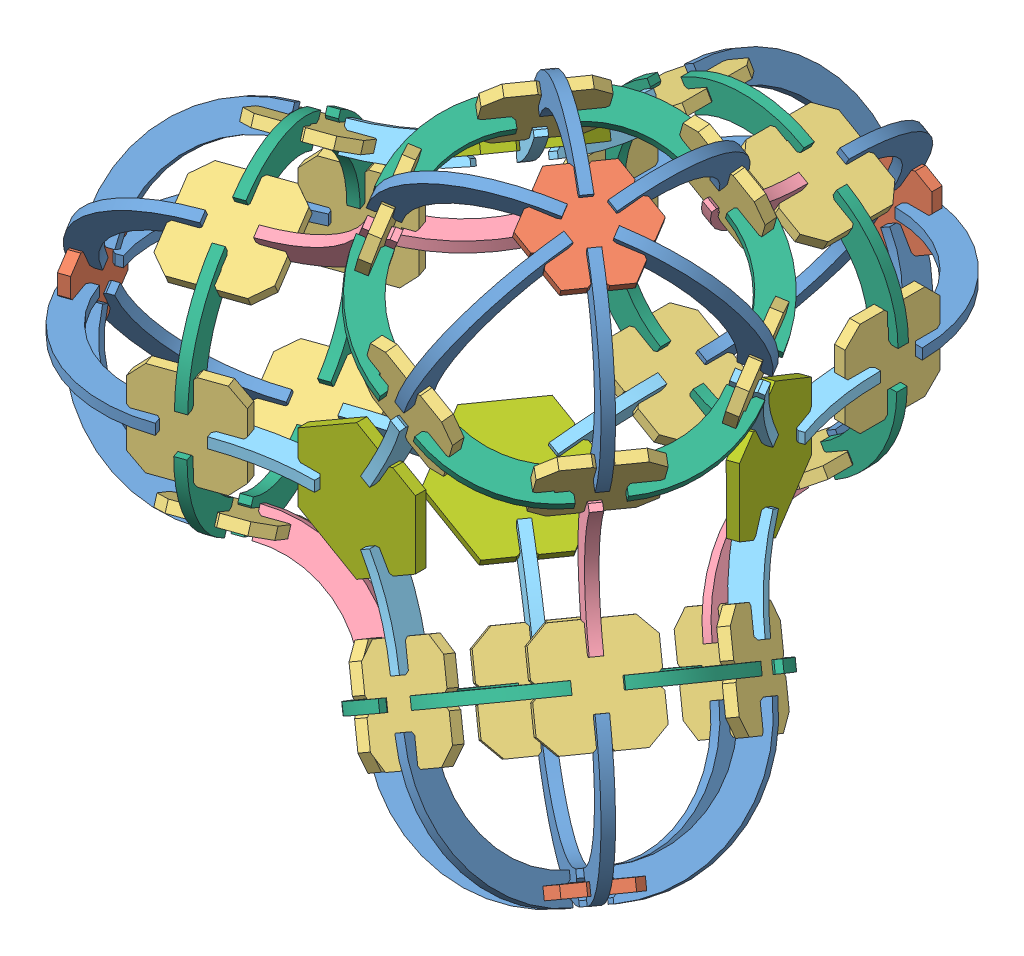
SolidWorks assembly All_Related, configuration Default. Lengths in mm.
Overall size (353.86 369.24 306.6).
102 component instances, 7 part files, 19 mates.
Components (placement in the parent):
- Casquete1-1: Casquete1 [Default] at origin size (138.23 154.01 159.67)
  - Circle-1: Circle [Default] at (-65.1069 8.9145 39.0884) size (50 3.85 50)
  - Hexagon-1: Hexagon [Default] at (-72.4274 10.8395 -4.4116) x (0.866025 0.5 0) z (-0.5 0.866025 0) size (40 54.12 34.64)
  - Circle-2: Circle [Default] at (-70.4343 3.5373 39.0884) x (0.5 -0.866025 0) z (0 0 1) size (50 3.85 50)
  - Circle-3: Circle [Default] at (-77.7548 5.4623 39.0884) x (-0.5 -0.866025 0) z (0 0 1) size (50 3.85 50)
  - square-1: square [Default] at (-97.4127 54.1153 46.5492) x (0.866025 0.5 0) z (0 0 1) size (34.92 3.85 34.92)
  - square-2: square [Default] at (-47.4422 54.1153 46.5492) x (0.866025 -0.5 0) z (0 0 1) size (34.92 3.85 34.92)
  - square-3: square [Default] at (-22.4569 10.8395 46.5492) x (0 -1 0) z (0 0 1) size (34.92 3.85 34.92)
  - Circle-8: Circle [Default] at (-79.7479 12.7645 39.0884) x (-1 0 0) z (0 0 1) size (50 3.85 50)
  - Circle-9: Circle [Default] at (-74.4206 18.1418 39.0884) x (-0.5 0.866025 0) z (0 0 1) size (50 3.85 50)
  - Circle-10: Circle [Default] at (-67.1001 16.2168 39.0884) x (0.5 0.866025 0) z (0 0 1) size (50 3.85 50)
  - square-7: square [Default] at (-47.4422 -32.4362 46.5492) x (-0.866025 -0.5 0) z (0 0 1) size (34.92 3.85 34.92)
  - square-8: square [Default] at (-97.4127 -32.4362 46.5492) x (-0.866025 0.5 0) z (0 0 1) size (34.92 3.85 34.92)
  - square-9: square [Default] at (-122.3979 10.8395 46.5492) x (0 1 0) z (0 0 1) size (34.92 3.85 34.92)
  - Circle120-1: Circle120 [Default] at (-34.3835 80.5835 102.8568) x (-0.166903 -0.289085 0.942641) z (0.471321 0.816351 0.333807) size (36.65 3.85 47.13)
  - CircleConcavo-1: CircleConcavo [Default] at (-27.4089 8.9145 54.1757) x (-1 0 0) z (0 0 -1) size (15.77 3.85 36.9)
  - CircleConcavo-2: CircleConcavo [Default] at (-96.6038 -27.1852 54.1757) x (0.5 0.866025 0) z (0 0 -1) size (15.77 3.85 36.9)
  - CircleConcavo-3: CircleConcavo [Default] at (-93.2696 50.7892 54.1757) x (0.5 -0.866025 0) z (0 0 -1) size (15.77 3.85 36.9)
  - Circle60-7: Circle60 [Default] at (-59.9685 17.4976 48.4742) x (0.5 0.866025 0) z (-0.866025 0.5 0) size (28.09 3.85 39.25)
  - Circle60-8: Circle60 [Default] at (-60.4319 3.3788 48.4742) x (1 0 0) z (0 1 0) size (28.09 3.85 39.25)
  - Circle60-9: Circle60 [Default] at (-72.8909 -3.2793 48.4742) x (0.5 -0.866025 0) z (0.866025 0.5 0) size (28.09 3.85 39.25)
  - Circle60-10: Circle60 [Default] at (-84.8864 4.1815 48.4742) x (-0.5 -0.866025 0) z (0.866025 -0.5 0) size (28.09 3.85 39.25)
  - Circle60-11: Circle60 [Default] at (-84.4229 18.3003 48.4742) x (-1 0 0) z (0 -1 0) size (28.09 3.85 39.25)
  - Circle60-12: Circle60 [Default] at (-71.964 24.9583 48.4742) x (-0.5 0.866025 0) z (-0.866025 -0.5 0) size (28.09 3.85 39.25)
- Casquete1-2: Casquete1 [Default] at (-35.9586 -74.0054 231.6496) x (-0.166903 0.289085 0.942641) z (-0.471321 0.816351 -0.333807) size (138.23 154.01 159.67)
  - Circle-1: Circle [Default] at (-65.1069 8.9145 39.0884) size (50 3.85 50)
  - Hexagon-1: Hexagon [Default] at (-72.4274 10.8395 -4.4116) x (0.866025 0.5 0) z (-0.5 0.866025 0) size (40 54.12 34.64)
  - Circle-2: Circle [Default] at (-70.4343 3.5373 39.0884) x (0.5 -0.866025 0) z (0 0 1) size (50 3.85 50)
  - Circle-3: Circle [Default] at (-77.7548 5.4623 39.0884) x (-0.5 -0.866025 0) z (0 0 1) size (50 3.85 50)
  - square-1: square [Default] at (-97.4127 54.1153 46.5492) x (0.866025 0.5 0) z (0 0 1) size (34.92 3.85 34.92)
  - square-2: square [Default] at (-47.4422 54.1153 46.5492) x (0.866025 -0.5 0) z (0 0 1) size (34.92 3.85 34.92)
  - square-3: square [Default] at (-22.4569 10.8395 46.5492) x (0 -1 0) z (0 0 1) size (34.92 3.85 34.92)
  - Circle-8: Circle [Default] at (-79.7479 12.7645 39.0884) x (-1 0 0) z (0 0 1) size (50 3.85 50)
  - Circle-9: Circle [Default] at (-74.4206 18.1418 39.0884) x (-0.5 0.866025 0) z (0 0 1) size (50 3.85 50)
  - Circle-10: Circle [Default] at (-67.1001 16.2168 39.0884) x (0.5 0.866025 0) z (0 0 1) size (50 3.85 50)
  - square-7: square [Default] at (-47.4422 -32.4362 46.5492) x (-0.866025 -0.5 0) z (0 0 1) size (34.92 3.85 34.92)
  - square-8: square [Default] at (-97.4127 -32.4362 46.5492) x (-0.866025 0.5 0) z (0 0 1) size (34.92 3.85 34.92)
  - square-9: square [Default] at (-122.3979 10.8395 46.5492) x (0 1 0) z (0 0 1) size (34.92 3.85 34.92)
  - Circle120-1: Circle120 [Default] at (-34.3835 80.5835 102.8568) x (-0.166903 -0.289085 0.942641) z (0.471321 0.816351 0.333807) size (36.65 3.85 47.13)
  - CircleConcavo-1: CircleConcavo [Default] at (-27.4089 8.9145 54.1757) x (-1 0 0) z (0 0 -1) size (15.77 3.85 36.9)
  - CircleConcavo-2: CircleConcavo [Default] at (-96.6038 -27.1852 54.1757) x (0.5 0.866025 0) z (0 0 -1) size (15.77 3.85 36.9)
  - CircleConcavo-3: CircleConcavo [Default] at (-93.2696 50.7892 54.1757) x (0.5 -0.866025 0) z (0 0 -1) size (15.77 3.85 36.9)
  - Circle60-7: Circle60 [Default] at (-59.9685 17.4976 48.4742) x (0.5 0.866025 0) z (-0.866025 0.5 0) size (28.09 3.85 39.25)
  - Circle60-8: Circle60 [Default] at (-60.4319 3.3788 48.4742) x (1 0 0) z (0 1 0) size (28.09 3.85 39.25)
  - Circle60-9: Circle60 [Default] at (-72.8909 -3.2793 48.4742) x (0.5 -0.866025 0) z (0.866025 0.5 0) size (28.09 3.85 39.25)
  - Circle60-10: Circle60 [Default] at (-84.8864 4.1815 48.4742) x (-0.5 -0.866025 0) z (0.866025 -0.5 0) size (28.09 3.85 39.25)
  - Circle60-11: Circle60 [Default] at (-84.4229 18.3003 48.4742) x (-1 0 0) z (0 -1 0) size (28.09 3.85 39.25)
  - Circle60-12: Circle60 [Default] at (-71.964 24.9583 48.4742) x (-0.5 0.866025 0) z (-0.866025 -0.5 0) size (28.09 3.85 39.25)
- Casquete1-3: Casquete1 [Default] at (-164.1397 21.6791 231.6496) x (0.333807 0 0.942641) z (0.942641 0 -0.333807) size (138.23 154.01 159.67)
  - Circle-1: Circle [Default] at (-65.1069 8.9145 39.0884) size (50 3.85 50)
  - Hexagon-1: Hexagon [Default] at (-72.4274 10.8395 -4.4116) x (0.866025 0.5 0) z (-0.5 0.866025 0) size (40 54.12 34.64)
  - Circle-2: Circle [Default] at (-70.4343 3.5373 39.0884) x (0.5 -0.866025 0) z (0 0 1) size (50 3.85 50)
  - Circle-3: Circle [Default] at (-77.7548 5.4623 39.0884) x (-0.5 -0.866025 0) z (0 0 1) size (50 3.85 50)
  - square-1: square [Default] at (-97.4127 54.1153 46.5492) x (0.866025 0.5 0) z (0 0 1) size (34.92 3.85 34.92)
  - square-2: square [Default] at (-47.4422 54.1153 46.5492) x (0.866025 -0.5 0) z (0 0 1) size (34.92 3.85 34.92)
  - square-3: square [Default] at (-22.4569 10.8395 46.5492) x (0 -1 0) z (0 0 1) size (34.92 3.85 34.92)
  - Circle-8: Circle [Default] at (-79.7479 12.7645 39.0884) x (-1 0 0) z (0 0 1) size (50 3.85 50)
  - Circle-9: Circle [Default] at (-74.4206 18.1418 39.0884) x (-0.5 0.866025 0) z (0 0 1) size (50 3.85 50)
  - Circle-10: Circle [Default] at (-67.1001 16.2168 39.0884) x (0.5 0.866025 0) z (0 0 1) size (50 3.85 50)
  - square-7: square [Default] at (-47.4422 -32.4362 46.5492) x (-0.866025 -0.5 0) z (0 0 1) size (34.92 3.85 34.92)
  - square-8: square [Default] at (-97.4127 -32.4362 46.5492) x (-0.866025 0.5 0) z (0 0 1) size (34.92 3.85 34.92)
  - square-9: square [Default] at (-122.3979 10.8395 46.5492) x (0 1 0) z (0 0 1) size (34.92 3.85 34.92)
  - Circle120-1: Circle120 [Default] at (-34.3835 80.5835 102.8568) x (-0.166903 -0.289085 0.942641) z (0.471321 0.816351 0.333807) size (36.65 3.85 47.13)
  - CircleConcavo-1: CircleConcavo [Default] at (-27.4089 8.9145 54.1757) x (-1 0 0) z (0 0 -1) size (15.77 3.85 36.9)
  - CircleConcavo-2: CircleConcavo [Default] at (-96.6038 -27.1852 54.1757) x (0.5 0.866025 0) z (0 0 -1) size (15.77 3.85 36.9)
  - CircleConcavo-3: CircleConcavo [Default] at (-93.2696 50.7892 54.1757) x (0.5 -0.866025 0) z (0 0 -1) size (15.77 3.85 36.9)
  - Circle60-7: Circle60 [Default] at (-59.9685 17.4976 48.4742) x (0.5 0.866025 0) z (-0.866025 0.5 0) size (28.09 3.85 39.25)
  - Circle60-8: Circle60 [Default] at (-60.4319 3.3788 48.4742) x (1 0 0) z (0 1 0) size (28.09 3.85 39.25)
  - Circle60-9: Circle60 [Default] at (-72.8909 -3.2793 48.4742) x (0.5 -0.866025 0) z (0.866025 0.5 0) size (28.09 3.85 39.25)
  - Circle60-10: Circle60 [Default] at (-84.8864 4.1815 48.4742) x (-0.5 -0.866025 0) z (0.866025 -0.5 0) size (28.09 3.85 39.25)
  - Circle60-11: Circle60 [Default] at (-84.4229 18.3003 48.4742) x (-1 0 0) z (0 -1 0) size (28.09 3.85 39.25)
  - Circle60-12: Circle60 [Default] at (-71.964 24.9583 48.4742) x (-0.5 0.866025 0) z (-0.866025 -0.5 0) size (28.09 3.85 39.25)
- Casquete1-4: Casquete1 [Default] at (-17.184 84.8449 231.6496) x (-0.166903 -0.289085 0.942641) z (-0.471321 -0.816351 -0.333807) size (138.23 154.01 159.67)
  - Circle-1: Circle [Default] at (-65.1069 8.9145 39.0884) size (50 3.85 50)
  - Hexagon-1: Hexagon [Default] at (-72.4274 10.8395 -4.4116) x (0.866025 0.5 0) z (-0.5 0.866025 0) size (40 54.12 34.64)
  - Circle-2: Circle [Default] at (-70.4343 3.5373 39.0884) x (0.5 -0.866025 0) z (0 0 1) size (50 3.85 50)
  - Circle-3: Circle [Default] at (-77.7548 5.4623 39.0884) x (-0.5 -0.866025 0) z (0 0 1) size (50 3.85 50)
  - square-1: square [Default] at (-97.4127 54.1153 46.5492) x (0.866025 0.5 0) z (0 0 1) size (34.92 3.85 34.92)
  - square-2: square [Default] at (-47.4422 54.1153 46.5492) x (0.866025 -0.5 0) z (0 0 1) size (34.92 3.85 34.92)
  - square-3: square [Default] at (-22.4569 10.8395 46.5492) x (0 -1 0) z (0 0 1) size (34.92 3.85 34.92)
  - Circle-8: Circle [Default] at (-79.7479 12.7645 39.0884) x (-1 0 0) z (0 0 1) size (50 3.85 50)
  - Circle-9: Circle [Default] at (-74.4206 18.1418 39.0884) x (-0.5 0.866025 0) z (0 0 1) size (50 3.85 50)
  - Circle-10: Circle [Default] at (-67.1001 16.2168 39.0884) x (0.5 0.866025 0) z (0 0 1) size (50 3.85 50)
  - square-7: square [Default] at (-47.4422 -32.4362 46.5492) x (-0.866025 -0.5 0) z (0 0 1) size (34.92 3.85 34.92)
  - square-8: square [Default] at (-97.4127 -32.4362 46.5492) x (-0.866025 0.5 0) z (0 0 1) size (34.92 3.85 34.92)
  - square-9: square [Default] at (-122.3979 10.8395 46.5492) x (0 1 0) z (0 0 1) size (34.92 3.85 34.92)
  - Circle120-1: Circle120 [Default] at (-34.3835 80.5835 102.8568) x (-0.166903 -0.289085 0.942641) z (0.471321 0.816351 0.333807) size (36.65 3.85 47.13)
  - CircleConcavo-1: CircleConcavo [Default] at (-27.4089 8.9145 54.1757) x (-1 0 0) z (0 0 -1) size (15.77 3.85 36.9)
  - CircleConcavo-2: CircleConcavo [Default] at (-96.6038 -27.1852 54.1757) x (0.5 0.866025 0) z (0 0 -1) size (15.77 3.85 36.9)
  - CircleConcavo-3: CircleConcavo [Default] at (-93.2696 50.7892 54.1757) x (0.5 -0.866025 0) z (0 0 -1) size (15.77 3.85 36.9)
  - Circle60-7: Circle60 [Default] at (-59.9685 17.4976 48.4742) x (0.5 0.866025 0) z (-0.866025 0.5 0) size (28.09 3.85 39.25)
  - Circle60-8: Circle60 [Default] at (-60.4319 3.3788 48.4742) x (1 0 0) z (0 1 0) size (28.09 3.85 39.25)
  - Circle60-9: Circle60 [Default] at (-72.8909 -3.2793 48.4742) x (0.5 -0.866025 0) z (0.866025 0.5 0) size (28.09 3.85 39.25)
  - Circle60-10: Circle60 [Default] at (-84.8864 4.1815 48.4742) x (-0.5 -0.866025 0) z (0.866025 -0.5 0) size (28.09 3.85 39.25)
  - Circle60-11: Circle60 [Default] at (-84.4229 18.3003 48.4742) x (-1 0 0) z (0 -1 0) size (28.09 3.85 39.25)
  - Circle60-12: Circle60 [Default] at (-71.964 24.9583 48.4742) x (-0.5 0.866025 0) z (-0.866025 -0.5 0) size (28.09 3.85 39.25)
- Circle120-1: Circle120 [Default] at (-151.8495 8.6129 102.5753) x (0.333807 0 0.942641) z (-0.942641 0 0.333807) size (36.65 3.85 47.13)
- Circle120-2: Circle120 [Default] at (-51.3728 -29.4782 54.1757) x (-0.5 0.866025 0) z (0 0 -1) size (36.65 3.85 47.13)
- vertex_concavo-6: vertex_concavo [Default] at (-72.4274 10.8395 186.2876) x (0.866025 0.5 0) z (0 0 1) size (50 43.3 19.21)
- vertex_concavo-7: vertex_concavo [Default] at (-102.611 63.0448 101.0519) x (0.576735 0.000355 -0.816931) z (-0.47199 0.816351 -0.332859) size (50 43.3 19.21)
- vertex_concavo-8: vertex_concavo [Default] at (-102.611 -41.3657 101.0519) x (0.86582 -0.500355 -0.00058) z (-0.47199 -0.816351 -0.332859) size (50 43.3 19.21)
- vertex_concavo-9: vertex_concavo [Default] at (-12.1246 10.8766 101.0519) x (-0.28806 -0.499645 -0.816931) z (0.942976 0.00058 -0.332859) size (50 43.3 19.21)
Mates (geometry in assembly coordinates):
- Coincident1: coincident: plane of Casquete1-1/Circle120-1 through (-29.573 81.2155 95.0157) normal (-0.166903 -0.289085 0.942641); plane of Casquete1-2/square-9
- Coincident4: coincident anti-aligned: plane of Casquete1-1/square-9 through (-126.2479 12.4629 58.7284) normal (0 0 1); plane of Circle120-1 through (-122.3979 12.4629 58.7284) normal (0 0 -1)
- Coincident6: coincident anti-aligned: plane of Casquete1-1/square-9 through (-122.3979 10.8395 46.5492) normal (1 0 0); plane of Circle120-1 through (-122.3979 12.4629 53.7284) normal (-1 0 0)
- Coincident7: coincident: plane of Casquete1-3/square-9 through (-161.6313 10.8395 98.0809) normal (-0.333807 0 -0.942641); plane of Circle120-2
- Coincident8: coincident anti-aligned: plane of Casquete1-3/square-9 through (-37.3592 -53.1471 91.3961) normal (0.866025 0.5 0); plane of Circle120-2
- Coincident9: coincident anti-aligned: plane of Casquete1-3/square-9 through (-31.6684 -55.3039 93.0651) normal (-0.471321 0.816351 -0.333807); plane of Circle120-2
- Coincident35: coincident: plane of Casquete1-2/CircleConcavo-1; plane of vertex_concavo-6
- Coincident36: coincident: plane of Casquete1-2/CircleConcavo-1; plane of vertex_concavo-6
- Coincident37: coincident: plane of Casquete1-4/CircleConcavo-2; plane of vertex_concavo-9
- Coincident38: coincident anti-aligned: plane of Casquete1-2/CircleConcavo-1 through (-62.0492 -3.2861 186.2876) normal (-0.5 0.866025 0); plane of vertex_concavo-6 through (-62.0492 -3.2861 190.1376) normal (0.5 -0.866025 0)
- Coincident39: coincident anti-aligned: plane of Casquete1-2/CircleConcavo-1 through (-64.5492 1.0441 190.1376) normal (0 0 -1); plane of vertex_concavo-6 through (-72.3558 10.7154 190.1376) normal (0 0 1)
- Coincident40: coincident anti-aligned: plane of Casquete1-2/CircleConcavo-1 through (-67.8834 -0.8809 293.7578) normal (-0.866025 -0.5 0); plane of vertex_concavo-6 through (-63.1975 -8.9971 190.1376) normal (0.866025 0.5 0)
- Coincident44: coincident anti-aligned: plane of Casquete1-2/square-9 through (-34.0022 -51.8649 91.2761) normal (-0.866025 -0.5 0); plane of Circle120-2 through (-22.0996 -72.4808 54.0099) normal (0.866025 0.5 0)
- Coincident45: coincident anti-aligned: plane of Casquete1-2/square-9 through (-31.6456 -55.9467 92.9452) normal (-0.471321 0.816351 -0.333807); plane of Circle120-2 through (-32.2882 -54.8337 96.5743) normal (0.471321 -0.816351 0.333807)
- Coincident46: coincident anti-aligned: plane of Casquete1-2/square-9 through (-28.0823 -65.9686 100.7338) normal (-0.166903 0.289085 0.942641); plane of Circle120-2 through (-29.9316 -58.9155 98.2434) normal (0.166903 -0.289085 -0.942641)
- Coincident47: coincident anti-aligned: plane of Casquete1-1/square-7 through (-47.1843 -36.7329 59.0099) normal (0 0 1); plane of Circle120-2 through (-43.8501 -34.8079 59.0099) normal (0 0 -1)
- Coincident48: coincident anti-aligned: plane of Casquete1-1/square-7 through (-47.4422 -32.4362 46.5492) normal (-0.5 0.866025 0); plane of Circle120-2 through (-45.7751 -31.4737 54.0099) normal (0.5 -0.866025 0)
- Coincident49: coincident anti-aligned: plane of Casquete1-1/square-7 through (-43.8501 -34.8079 64.0099) normal (-0.866025 -0.5 0); plane of Circle120-2 through (-22.0996 -72.4808 54.0099) normal (0.866025 0.5 0)
- Coincident50: coincident anti-aligned: line of Casquete1-1/Hexagon-1 through (-72.4274 10.8395 -4.4116) axis (0 0 -1); line of vertex_concavo-6 through (-72.4274 10.8395 186.2876) axis (0 0 1)
